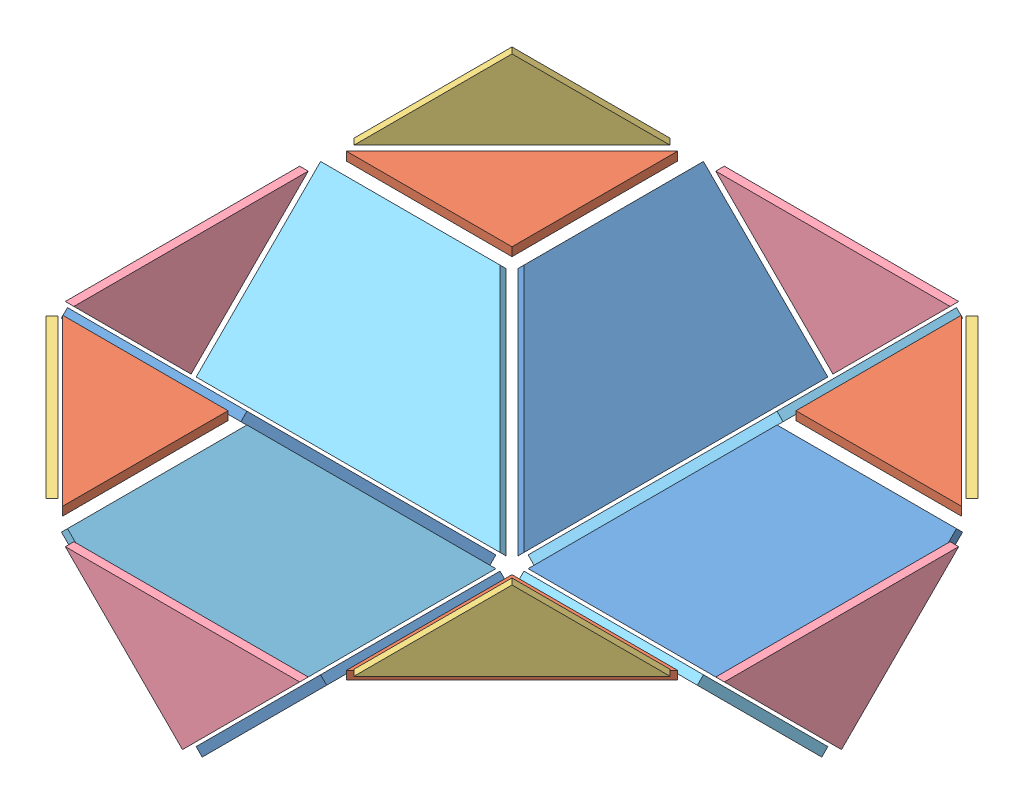
SolidWorks assembly Face, configuration Default. Lengths in mm.
Overall size (230.41 76.56 230.41).
52 component instances, 12 part files, 6 mates.
Components (placement in the parent):
- Face Quarter-1: Face Quarter [Default] at origin size (152.13 76.56 114.47)
  - Goux Like-1: Goux Like [Default] at origin (suppressed, hidden)
  - trapezoid-1: trapezoid [Default] at origin size (45.63 45.63 106.26)
  - triangle 1-1: triangle 1 [Default] at origin size (57.93 3 57.93)
  - triangle 2-1: triangle 2 [Default] at origin size (57.43 27.65 57.43)
  - triangle 3-1: triangle 3 [Default] at origin size (81.93 40.97 3)
  - triangle 4-1: triangle 4 [Default] at origin size (106.26 45.63 45.63)
  - Joiner_1-1: Joiner_1 [Default] at (80.4015 -113.7049 80.4015) x (0 -1 0) z (-0.707107 0 0.707107) (suppressed, hidden)
  - Joiner_2-1: Joiner_2 [Default] at (0 -160.803 0) x (-0.707107 -0.707107 0) z (0 0 1) (suppressed, hidden)
  - Joiner_3-1: Joiner_3 [Default] at (80.4015 -80.4015 113.7049) x (0.707107 -0.707107 0) z (-0.707107 -0.707107 0) (suppressed, hidden)
  - Joiner_Open - 1-2: Joiner_Open - 1 [Default] at (0 -113.7049 113.7049) x (0 1 0) z (1 0 0) (suppressed, hidden)
  - Joiner_Open - 2-1: Joiner_Open - 2 [Default] at (47.0981 -113.7049 0) x (-1 0 0) z (0 0 1) (suppressed, hidden)
  - Joiner_Open - 3-1: Joiner_Open - 3 [Default] at (53.601 -107.202 53.601) x (-0.816497 0.408248 0.408248) z (0.57735 0.57735 0.57735) (suppressed, hidden)
- Face Quarter-2: Face Quarter [Default] x (0 0 -1) z (1 0 0) size (152.13 76.56 114.47)
  - Goux Like-1: Goux Like [Default] at origin (suppressed, hidden)
  - trapezoid-1: trapezoid [Default] at origin size (45.63 45.63 106.26)
  - triangle 1-1: triangle 1 [Default] at origin size (57.93 3 57.93)
  - triangle 2-1: triangle 2 [Default] at origin size (57.43 27.65 57.43)
  - triangle 3-1: triangle 3 [Default] at origin size (81.93 40.97 3)
  - triangle 4-1: triangle 4 [Default] at origin size (106.26 45.63 45.63)
  - Joiner_1-1: Joiner_1 [Default] at (80.4015 -113.7049 80.4015) x (0 -1 0) z (-0.707107 0 0.707107) (suppressed, hidden)
  - Joiner_2-1: Joiner_2 [Default] at (0 -160.803 0) x (-0.707107 -0.707107 0) z (0 0 1) (suppressed, hidden)
  - Joiner_3-1: Joiner_3 [Default] at (80.4015 -80.4015 113.7049) x (0.707107 -0.707107 0) z (-0.707107 -0.707107 0) (suppressed, hidden)
  - Joiner_Open - 1-2: Joiner_Open - 1 [Default] at (0 -113.7049 113.7049) x (0 1 0) z (1 0 0) (suppressed, hidden)
  - Joiner_Open - 2-1: Joiner_Open - 2 [Default] at (47.0981 -113.7049 0) x (-1 0 0) z (0 0 1) (suppressed, hidden)
  - Joiner_Open - 3-1: Joiner_Open - 3 [Default] at (53.601 -107.202 53.601) x (-0.816497 0.408248 0.408248) z (0.57735 0.57735 0.57735) (suppressed, hidden)
- Face Quarter-3: Face Quarter [Default] x (-1 0 0) z (0 0 -1) size (152.13 76.56 114.47)
  - Goux Like-1: Goux Like [Default] at origin (suppressed, hidden)
  - trapezoid-1: trapezoid [Default] at origin size (45.63 45.63 106.26)
  - triangle 1-1: triangle 1 [Default] at origin size (57.93 3 57.93)
  - triangle 2-1: triangle 2 [Default] at origin size (57.43 27.65 57.43)
  - triangle 3-1: triangle 3 [Default] at origin size (81.93 40.97 3)
  - triangle 4-1: triangle 4 [Default] at origin size (106.26 45.63 45.63)
  - Joiner_1-1: Joiner_1 [Default] at (80.4015 -113.7049 80.4015) x (0 -1 0) z (-0.707107 0 0.707107) (suppressed, hidden)
  - Joiner_2-1: Joiner_2 [Default] at (0 -160.803 0) x (-0.707107 -0.707107 0) z (0 0 1) (suppressed, hidden)
  - Joiner_3-1: Joiner_3 [Default] at (80.4015 -80.4015 113.7049) x (0.707107 -0.707107 0) z (-0.707107 -0.707107 0) (suppressed, hidden)
  - Joiner_Open - 1-2: Joiner_Open - 1 [Default] at (0 -113.7049 113.7049) x (0 1 0) z (1 0 0) (suppressed, hidden)
  - Joiner_Open - 2-1: Joiner_Open - 2 [Default] at (47.0981 -113.7049 0) x (-1 0 0) z (0 0 1) (suppressed, hidden)
  - Joiner_Open - 3-1: Joiner_Open - 3 [Default] at (53.601 -107.202 53.601) x (-0.816497 0.408248 0.408248) z (0.57735 0.57735 0.57735) (suppressed, hidden)
- Face Quarter-4: Face Quarter [Default] x (0 0 1) z (-1 0 0) size (152.13 76.56 114.47)
  - Goux Like-1: Goux Like [Default] at origin (suppressed, hidden)
  - trapezoid-1: trapezoid [Default] at origin size (45.63 45.63 106.26)
  - triangle 1-1: triangle 1 [Default] at origin size (57.93 3 57.93)
  - triangle 2-1: triangle 2 [Default] at origin size (57.43 27.65 57.43)
  - triangle 3-1: triangle 3 [Default] at origin size (81.93 40.97 3)
  - triangle 4-1: triangle 4 [Default] at origin size (106.26 45.63 45.63)
  - Joiner_1-1: Joiner_1 [Default] at (80.4015 -113.7049 80.4015) x (0 -1 0) z (-0.707107 0 0.707107) (suppressed, hidden)
  - Joiner_2-1: Joiner_2 [Default] at (0 -160.803 0) x (-0.707107 -0.707107 0) z (0 0 1) (suppressed, hidden)
  - Joiner_3-1: Joiner_3 [Default] at (80.4015 -80.4015 113.7049) x (0.707107 -0.707107 0) z (-0.707107 -0.707107 0) (suppressed, hidden)
  - Joiner_Open - 1-2: Joiner_Open - 1 [Default] at (0 -113.7049 113.7049) x (0 1 0) z (1 0 0) (suppressed, hidden)
  - Joiner_Open - 2-1: Joiner_Open - 2 [Default] at (47.0981 -113.7049 0) x (-1 0 0) z (0 0 1) (suppressed, hidden)
  - Joiner_Open - 3-1: Joiner_Open - 3 [Default] at (53.601 -107.202 53.601) x (-0.816497 0.408248 0.408248) z (0.57735 0.57735 0.57735) (suppressed, hidden)
Mates (geometry in assembly coordinates):
- Coincident1: coincident aligned: line of Face Quarter-2 through (84.2108 0 30.9271) axis (0 0 1)
- Coincident2: coincident aligned: line of Face Quarter-2 through (0 125.9164 24.1021) axis (0 0 1)
- Coincident3: coincident aligned: line of Face Quarter-3 through (84.2108 0 30.9271) axis (0 0 1)
- Coincident4: coincident anti-aligned: line of Face Quarter-3 through (0 167.344 -36.4768) axis (0 0 -1)
- Coincident5: coincident aligned: line of Face Quarter-4 through (84.2108 0 30.9271) axis (0 0 1)
- Coincident6: coincident anti-aligned: line of Face Quarter-4 through (0 125.9164 -24.1021) axis (0 0 -1)
